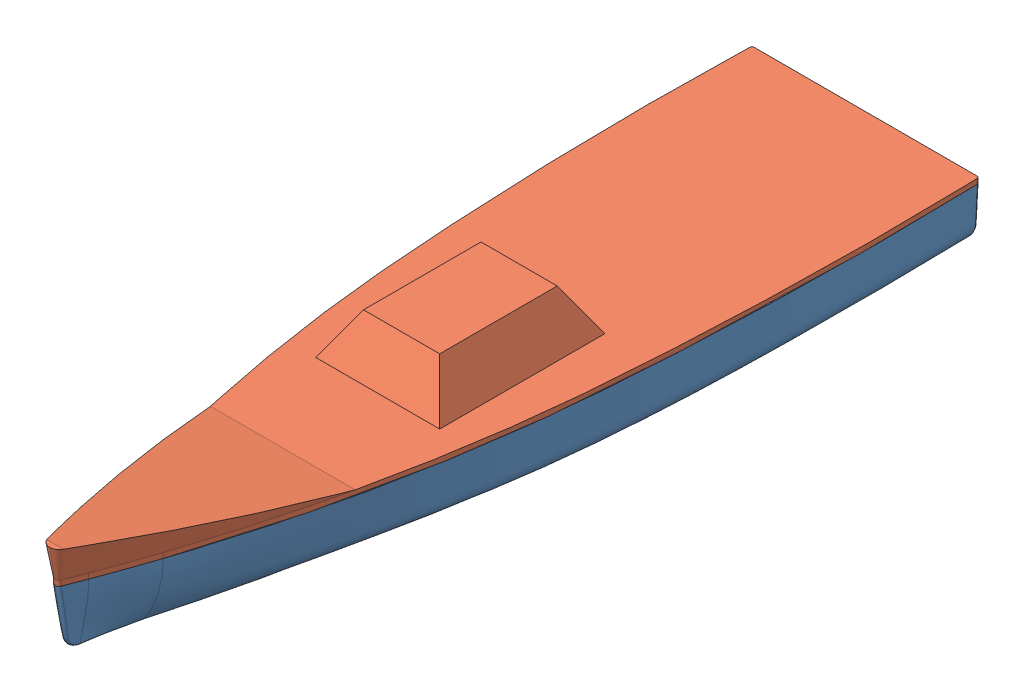
SolidWorks assembly Deck & Hull 2, configuration Default. Lengths in mm.
Overall size (590.36 317.51 2017.83).
2 component instances, 2 part files, 3 mates.
Components (placement in the parent):
- Hull 9.2 rounder bow-1: Hull 9.2 rounder bow [JustSolid] at origin size (590.36 218.85 2004.6)
- Deck test-1: Deck test [Default] at (-7.7182 0 648.2956) size (572.24 114.31 2007.13)
Mates (geometry in assembly coordinates):
- Coincident1: coincident anti-aligned: plane of Hull 9.2 rounder bow-1 through (279.4 0 0) normal (0 1 0); plane of Deck test-1 through (5.3677 0 1992.242) normal (0 -1 0)
- Coincident2: coincident aligned: plane of Hull 9.2 rounder bow-1 through (0 0 0) normal (0 0 -1); plane of Deck test-1 through (274.4604 12.7 0) normal (0 0 -1)
- Coincident3: coincident aligned: plane of Hull 9.2 rounder bow-1 through (0 0 0) normal (1 0 0); line of Deck test-1 through (0 12.7 1993.9) axis (0 0 -1)
